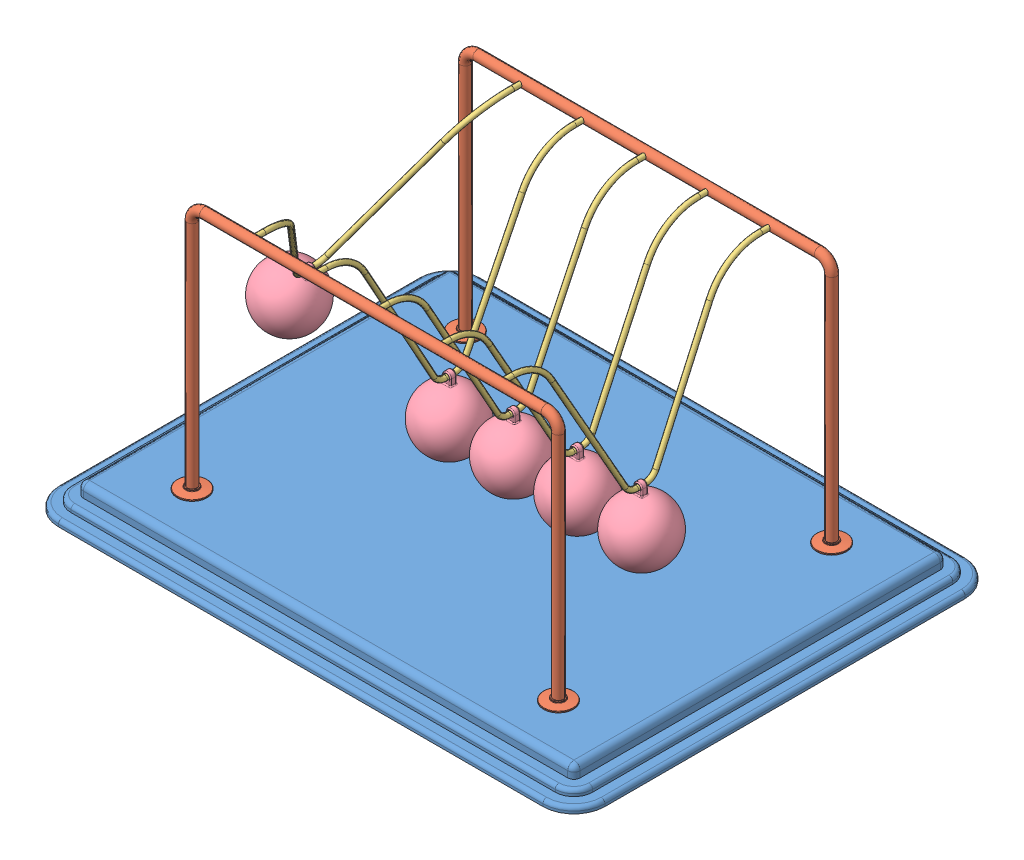
SolidWorks assembly Newtons Cradle NewtonsCradle 0236, configuration Default. Lengths in mm.
Overall size (440 222 340).
13 component instances, 4 part files, 34 mates.
Components (placement in the parent):
- Base NewtonsCradle 0236-1: Base NewtonsCradle 0236 [Default] at (-16.2968 -4.1587 11.425) size (440 20 340)
- frame NewtonsCradle 0236-1: frame NewtonsCradle 0236 [Default] at (-16.2968 144.4547 -98.575) size (319 202 24)
- frame NewtonsCradle 0236-2: frame NewtonsCradle 0236 [Default] at (-16.2968 144.4547 121.425) x (-1 0 0) z (0 0 -1) size (319 202 24)
- Hanging thing NewtonsCradle 0236-1: Hanging thing NewtonsCradle 0236 [Default] at (-157.6326 134.1825 11.425) x (0 0 1) z (-0.859985 0.510319 0) size (220 129 4)
- Hanging thing NewtonsCradle 0236-2: Hanging thing NewtonsCradle 0236 [Default] at (-66.576 122.8418 11.425) x (0 0 1) z (-0.999994 0.003446 0) size (220 129 4)
- Hanging thing NewtonsCradle 0236-3: Hanging thing NewtonsCradle 0236 [Default] at (-15.6923 122.8436 11.425) x (0 0 1) z (-0.999972 -0.007464 0) size (220 129 4)
- Hanging thing NewtonsCradle 0236-4: Hanging thing NewtonsCradle 0236 [Default] at (35.2213 122.8555 11.425) x (0 0 1) z (-0.999824 -0.018742 0) size (220 129 4)
- Hanging thing NewtonsCradle 0236-5: Hanging thing NewtonsCradle 0236 [Default] at (86.0287 122.8747 11.425) x (0 0 1) z (-0.999588 -0.028711 0) size (220 129 4)
- Sphere NewtonsCradle 0236-1: Sphere NewtonsCradle 0236 [Default] at (-195.3962 70.5436 11.425) x (0.859985 -0.510319 0) z (0 0 1) size (50 58.5 50)
- Sphere NewtonsCradle 0236-2: Sphere NewtonsCradle 0236 [Default] at (88.1533 48.9052 11.425) x (0.999588 0.028711 0) z (0 0 1) size (50 58.5 50)
- Sphere NewtonsCradle 0236-3: Sphere NewtonsCradle 0236 [Default] at (-15.14 48.8456 11.425) x (0.999972 0.007464 0) z (0 0 1) size (50 58.5 50)
- Sphere NewtonsCradle 0236-4: Sphere NewtonsCradle 0236 [Default] at (36.6081 48.8685 11.425) x (0.999824 0.018742 0) z (0 0 1) size (50 58.5 50)
- Sphere NewtonsCradle 0236-5: Sphere NewtonsCradle 0236 [Default] at (-66.831 48.8422 11.425) x (0.999994 -0.003446 0) z (0 0 1) size (50 58.5 50)
Mates (geometry in assembly coordinates):
- Coincident1: coincident anti-aligned: plane of Base-1 through (-211.2968 5.8413 156.425) normal (0 1 0); plane of frame-2 through (-175.7968 5.8413 121.425) normal (0 -1 0)
- Coincident2: coincident anti-aligned: plane of Base-1 through (-211.2968 5.8413 156.425) normal (0 1 0); plane of frame-1 through (143.2032 5.8413 -98.575) normal (0 -1 0)
- Concentric1: concentric anti-aligned: cylinder of frame-1 through (-116.2968 203.8413 -94.575) axis (0 0 -1) radius 2; cylinder of frame-2 through (-116.2968 203.8413 117.425) axis (0 0 1) radius 2
- Concentric2: concentric anti-aligned: cylinder of frame-1 through (83.7032 203.8413 -94.575) axis (0 0 -1) radius 2; cylinder of frame-2 through (83.7032 203.8413 117.425) axis (0 0 1) radius 2
- Distance1: distance = 60 mm: plane of frame-1 through (-16.2968 144.4547 -98.575) normal (0 0 1); line of Base-1 through (-211.2968 -12.1587 -158.575) axis (1 0 0)
- Distance2: distance = 60 mm: line of Base-1 through (178.7032 -12.1587 181.425) axis (-1 0 0); plane of frame-2 through (-16.2968 144.4547 121.425) normal (0 0 -1)
- Distance3: distance = 220 mm: plane of frame-2 through (-16.2968 144.4547 121.425) normal (-1 0 0); line of Base-1 through (-236.2968 -12.1587 156.425) axis (0 0 -1)
- Concentric3: concentric anti-aligned: cylinder of frame-1 through (-116.2968 203.8413 -94.575) axis (0 0 -1) radius 2; cylinder of Hanging thing-1 through (-116.2968 203.8413 111.425) axis (0 0 1) radius 2
- Concentric4: concentric anti-aligned: cylinder of frame-1 through (-116.2968 203.8413 -94.575) axis (0 0 -1) radius 2; cylinder of Hanging thing-1 through (-116.2968 203.8413 -98.575) axis (0 0 1) radius 2
- Concentric5: concentric aligned: cylinder of frame-2 through (-66.2968 203.8413 117.425) axis (0 0 1) radius 2; cylinder of Hanging thing-2 through (-66.2968 203.8413 111.425) axis (0 0 1) radius 2
- Concentric6: concentric aligned: cylinder of frame-2 through (-16.2968 203.8413 117.425) axis (0 0 1) radius 2; cylinder of Hanging thing-3 through (-16.2968 203.8413 111.425) axis (0 0 1) radius 2
- Concentric7: concentric aligned: cylinder of frame-2 through (33.7032 203.8413 117.425) axis (0 0 1) radius 2; cylinder of Hanging thing-4 through (33.7032 203.8413 111.425) axis (0 0 1) radius 2
- Concentric8: concentric aligned: cylinder of frame-2 through (83.7032 203.8413 117.425) axis (0 0 1) radius 2; cylinder of Hanging thing-5 through (83.7032 203.8413 111.425) axis (0 0 1) radius 2
- Coincident5: coincident anti-aligned: plane of frame-2 through (83.7032 203.8413 121.425) normal (0 0 -1); plane of Hanging thing-5 through (83.7032 203.8413 121.425) normal (0 0 1)
- Coincident6: coincident anti-aligned: plane of frame-2 through (33.7032 203.8413 121.425) normal (0 0 -1); plane of Hanging thing-4 through (33.7032 203.8413 121.425) normal (0 0 1)
- Coincident7: coincident anti-aligned: plane of frame-2 through (-16.2968 203.8413 121.425) normal (0 0 -1); plane of Hanging thing-3 through (-16.2968 203.8413 121.425) normal (0 0 1)
- Coincident8: coincident anti-aligned: plane of frame-2 through (-66.2968 203.8413 121.425) normal (0 0 -1); plane of Hanging thing-2 through (-66.2968 203.8413 121.425) normal (0 0 1)
- Coincident9: coincident anti-aligned: plane of frame-2 through (-116.2968 203.8413 121.425) normal (0 0 -1); plane of Hanging thing-1 through (-116.2968 203.8413 121.425) normal (0 0 1)
- Concentric9: concentric anti-aligned: cylinder of Hanging thing-1 through (-117.0163 78.8434 7.925) axis (0 0 1) radius 2; cylinder of Sphere-1 through (-117.0163 78.8434 13.925) axis (0 0 -1) radius 2
- Concentric13: concentric anti-aligned: cylinder of Hanging thing-2 through (-66.7276 78.842 7.925) axis (0 0 1) radius 2; cylinder of Sphere-5 through (-66.7276 78.842 13.925) axis (0 0 -1) radius 2
- Concentric15: concentric anti-aligned: cylinder of Hanging thing-3 through (-15.3639 78.8448 7.925) axis (0 0 1) radius 2; cylinder of Sphere-3 through (-15.3639 78.8448 13.925) axis (0 0 -1) radius 2
- Concentric16: concentric anti-aligned: cylinder of Hanging thing-5 through (87.292 78.8928 7.925) axis (0 0 1) radius 2; cylinder of Sphere-2 through (87.292 78.8928 13.925) axis (0 0 -1) radius 2
- Concentric17: concentric anti-aligned: cylinder of Hanging thing-4 through (36.0459 78.8632 7.925) axis (0 0 1) radius 2; cylinder of Sphere-4 through (36.0459 78.8632 13.925) axis (0 0 -1) radius 2
- Parallel1: parallel anti-aligned: plane of Hanging thing-1; plane of Sphere-1
- Coincident22: coincident anti-aligned: plane of Hanging thing-1; plane of Sphere-1
- Coincident12: coincident aligned: plane of Hanging thing-2 through (-66.576 122.8418 11.425) normal (0 0 1); plane of Sphere-5 through (-66.831 48.8422 11.425) normal (0 0 1)
- Coincident10: coincident aligned: plane of Hanging thing-1 through (-116.763 122.8426 11.425) normal (0 0 1); plane of Sphere-1 through (-118.5806 48.8842 11.425) normal (0 0 1)
- Coincident13: coincident anti-aligned: plane of Hanging thing-2 through (-66.576 122.8418 11.425) normal (-0.999994 0.003446 0); plane of Sphere-5 through (-66.831 48.8422 11.425) normal (0.999994 -0.003446 0)
- Coincident14: coincident anti-aligned: plane of Hanging thing-3 through (-15.6923 122.8436 11.425) normal (-0.999972 -0.007464 0); plane of Sphere-3 through (-15.14 48.8456 11.425) normal (0.999972 0.007464 0)
- Coincident15: coincident aligned: plane of Hanging thing-3 through (-15.6923 122.8436 11.425) normal (0 0 1); plane of Sphere-3 through (-15.14 48.8456 11.425) normal (0 0 1)
- Coincident18: coincident aligned: plane of Hanging thing-4 through (35.2213 122.8555 11.425) normal (0 0 1); plane of Sphere-4 through (36.6081 48.8685 11.425) normal (0 0 1)
- Coincident19: coincident anti-aligned: plane of Hanging thing-4 through (35.2213 122.8555 11.425) normal (-0.999824 -0.018742 0); plane of Sphere-4 through (36.6081 48.8685 11.425) normal (0.999824 0.018742 0)
- Coincident20: coincident anti-aligned: plane of Hanging thing-5 through (86.0287 122.8747 11.425) normal (-0.999588 -0.028711 0); plane of Sphere-2 through (88.1533 48.9052 11.425) normal (0.999588 0.028711 0)
- Coincident21: coincident aligned: plane of Hanging thing-5 through (86.0287 122.8747 11.425) normal (0 0 1); plane of Sphere-2 through (88.1533 48.9052 11.425) normal (0 0 1)
